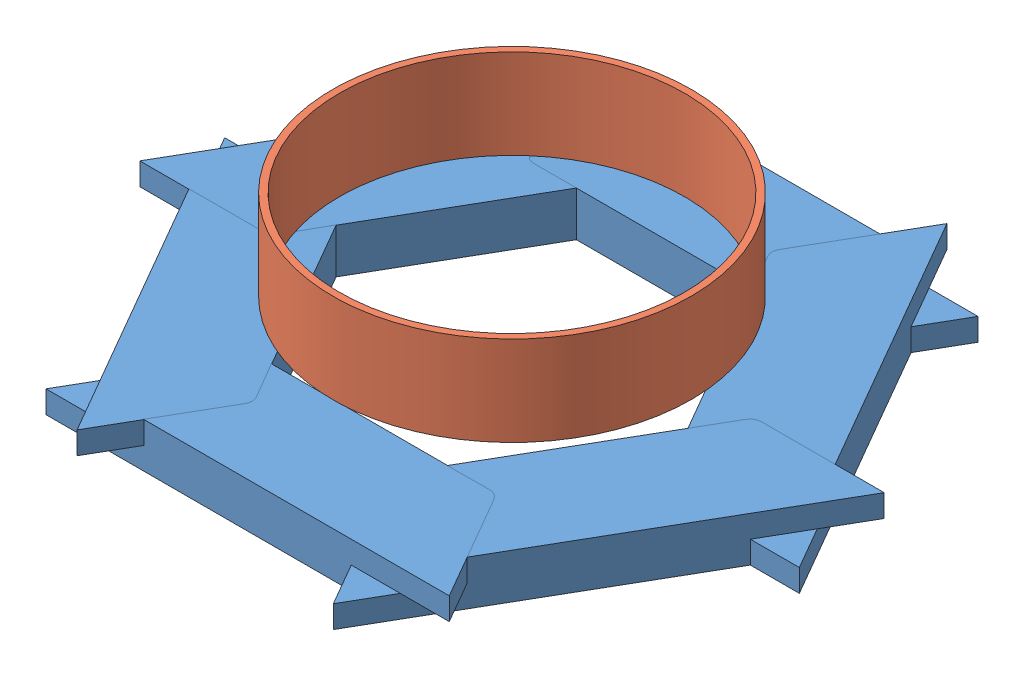
SolidWorks assembly Кольцо160, configuration По умолчанию. Lengths in mm.
Overall size (294.38 71.81 273.88).
7 component instances, 2 part files, 4 mates.
Components (placement in the parent):
- Планка20-1: Планка20 [По умолчанию] at (-90 0 -68) size (180 20 50)
- Планка20-2: Планка20 [По умолчанию] at (-103.8897 0 43.9423) x (0.5 0 -0.866025) z (0.866025 0 0.5) size (180 20 50)
- Планка20-3: Планка20 [По умолчанию] at (-13.8897 0 111.9423) x (-0.5 0 -0.866025) z (0.866025 0 -0.5) size (180 20 50)
- Планка20-4: Планка20 [По умолчанию] at (90 0 68) x (-1 0 0) z (0 0 -1) size (180 20 50)
- Планка20-5: Планка20 [По умолчанию] at (103.8897 0 -43.9423) x (-0.5 0 0.866025) z (-0.866025 0 -0.5) size (180 20 50)
- Планка20-6: Планка20 [По умолчанию] at (13.8897 0 -111.9423) x (0.5 0 0.866025) z (-0.866025 0 0.5) size (180 20 50)
- Труба160-1: Труба160 [По умолчанию] at (0 31.8051 0) x (0.997104 0 -0.076054) z (0.076054 0 0.997104) size (160 40 160)
Mates (geometry in assembly coordinates):
- Совпадение1: coincident anti-aligned: plane of Планка20-1 through (90 0 -68) normal (0 -1 0); plane of assembly through (0 0 0) normal (0 1 0)
- Расстояние1: distance = 68 mm aligned: plane of Планка20-1 through (90 0 -68) normal (0 0 1); plane of assembly through (0 0 0) normal (0 0 1)
- Расстояние2: distance = 90 mm aligned: plane of Планка20-1 through (-90 0 -68) normal (1 0 0); plane of assembly through (0 0 0) normal (1 0 0)
- Концентричный1: concentric anti-aligned: cylinder of Труба160-1 through (0 71.8051 0) axis (0 -1 0) radius 77
